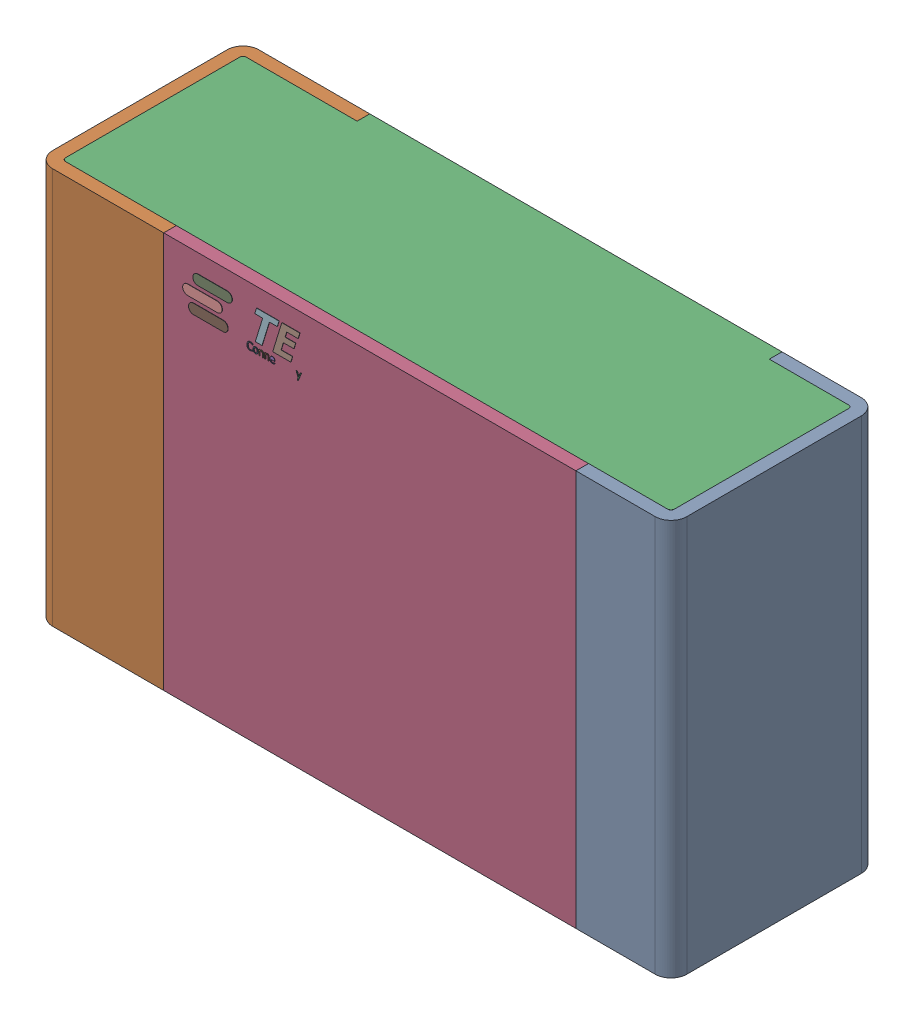
SolidWorks assembly Res_TE_Connectivity_CPF0805B66R5E1_eec.step, configuration Default. Lengths in mm.
Overall size (2 1.25 0.65).
4 component instances, 4 part files, 0 mates.
Components (placement in the parent):
- 1.step-1: 1.step [Default] at origin size (2 1.25 0.65)
- 2.step-1: 2.step [Default] at origin size (1.92 1.25 0.61)
- 3.step-1: 3.step [Default] at origin size (1.3 1.25 0.04)
- TE connectivity Logo 1 (2).step-1: TE connectivity Logo 1 (2).step [Default] at (5.4285 0.313 0.551) x (-1 0 0) z (0 0 1) size (0.37 0.13 0.11)
